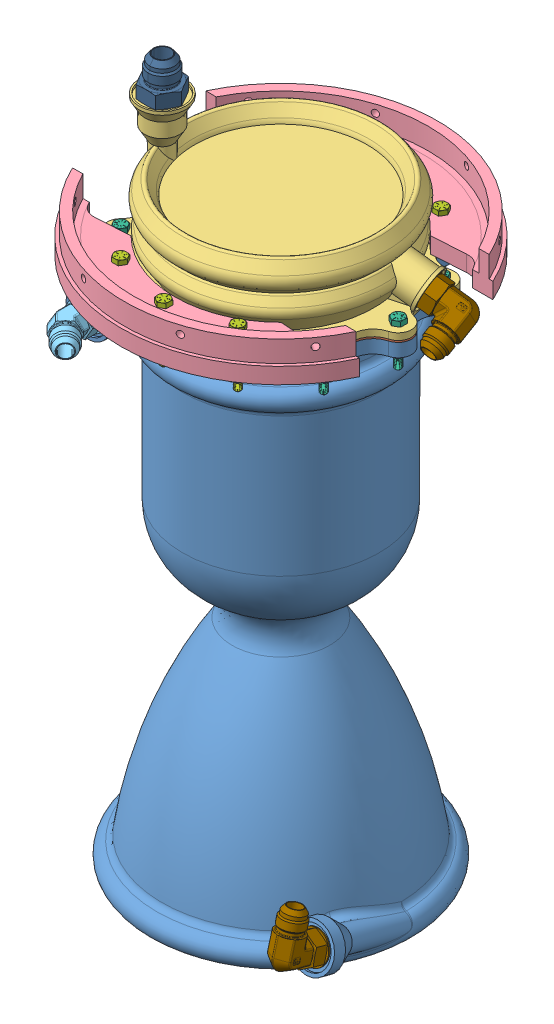
SolidWorks assembly 10013-R01_Engine, configuration Default. Lengths in mm.
Overall size (302.89 639.04 304.8).
32 component instances, 10 part files, 30 mates.
Components (placement in the parent):
- 13100_R02_Thrust_Chamber-2: 13100_R02_Thrust_Chamber [Default] at origin size (262.96 497.78 253.25)
- 13101-R01_TCA_GASKET-2: 13101-R01_TCA_GASKET [Default] at (0 280.7399 0) size (248.92 1.59 248.92)
- 13008-R01_Injector_Plate-2: 13008-R01_Injector_Plate [Default] at (150.3244 162.3751 158.3501) x (-0.965926 0 0.258819) z (-0.258819 0 -0.965926) size (243.88 107.11 241.3)
- 13007-R01_Thrust_Mount-3: 13007-R01_Thrust_Mount [Default] at (0 288.6774 0) x (0 0 -1) z (1 0 0) size (304.8 35.64 277.08)
- 15011-R01_10_FITTING_45-2: 15011-R01_10_FITTING_45 [Default] at (-93.6214 237.7504 111.76) size (44.94 39.22 63.51)
- 16011-R01_S_BOLT-13: 16011-R01_S_BOLT [90201A117] at (96.787 272.0087 55.88) x (0 -1 0) z (0 0 1) size (43.33 12.83 11.11)
- 16012-R01_L_BOLT-7: 16012-R01_L_BOLT [91257A550] at (55.88 280.7002 96.787) x (0 -1 0) z (0 0 1) size (55.63 12.83 11.11)
- 16013-R01_NUT-33: 16013-R01_NUT [94895A029] at (96.787 265.2618 55.88) x (-1 0 0) z (0 1 0) size (11.11 12.83 7.14)
- 15012-R01_10_FITTING_90-1: 15012-R01_10_FITTING_90 [Default] at (112.0104 282.4233 -26.0534) x (0.05538 -0.433018 0.899683) z (0.447836 0.816118 0.365232) size (51.49 55.55 29.29)
- 15012-R01_10_FITTING_90-2: 15012-R01_10_FITTING_90 [Default] at (102.5614 -170.5898 88.4045) x (0 0.965926 -0.258819) z (1 0 0) size (51.49 55.55 29.29)
- 15013-R01_12_FITTING_S-1: 15013-R01_12_FITTING_S [Default] at (-89.1216 396.9815 23.8801) x (0 1 0) z (0 0 1) size (50.04 36.67 31.75)
- 16011-R01_S_BOLT-14: 16011-R01_S_BOLT [90201A117] at (111.76 272.0087 0) x (0 -1 0) z (0.5 0 0.866025) size (43.33 12.83 11.11)
- 16011-R01_S_BOLT-15: 16011-R01_S_BOLT [90201A117] at (96.787 272.0087 -55.88) x (0 -1 0) z (0.866025 0 0.5) size (43.33 12.83 11.11)
- 16012-R01_L_BOLT-8: 16012-R01_L_BOLT [91257A550] at (0 280.7002 111.76) x (0 -1 0) z (-0.5 0 0.866025) size (55.63 12.83 11.11)
- 16012-R01_L_BOLT-9: 16012-R01_L_BOLT [91257A550] at (-55.88 280.7002 96.787) x (0 -1 0) z (-0.866025 0 0.5) size (55.63 12.83 11.11)
- 16012-R01_L_BOLT-10: 16012-R01_L_BOLT [91257A550] at (-55.88 280.7002 -96.787) x (0 -1 0) z (0 0 -1) size (55.63 12.83 11.11)
- 16012-R01_L_BOLT-11: 16012-R01_L_BOLT [91257A550] at (0 280.7002 -111.76) x (0 -1 0) z (0.5 0 -0.866025) size (55.63 12.83 11.11)
- 16012-R01_L_BOLT-12: 16012-R01_L_BOLT [91257A550] at (55.88 280.7002 -96.787) x (0 -1 0) z (0.866025 0 -0.5) size (55.63 12.83 11.11)
- 16011-R01_S_BOLT-16: 16011-R01_S_BOLT [90201A117] at (-96.787 272.0087 -55.88) x (0 -1 0) z (0 0 -1) size (43.33 12.83 11.11)
- 16011-R01_S_BOLT-17: 16011-R01_S_BOLT [90201A117] at (-111.76 272.0087 0) x (0 -1 0) z (-0.5 0 -0.866025) size (43.33 12.83 11.11)
- 16011-R01_S_BOLT-18: 16011-R01_S_BOLT [90201A117] at (-96.787 272.0087 55.88) x (0 -1 0) z (-0.866025 0 -0.5) size (43.33 12.83 11.11)
- 16013-R01_NUT-34: 16013-R01_NUT [94895A029] at (111.76 265.2618 0) x (-0.866025 0 0.5) z (0 1 0) size (11.11 12.83 7.14)
- 16013-R01_NUT-35: 16013-R01_NUT [94895A029] at (96.787 265.2618 -55.88) x (-0.5 0 0.866025) z (0 1 0) size (11.11 12.83 7.14)
- 16013-R01_NUT-36: 16013-R01_NUT [94895A029] at (55.88 265.2618 -96.787) x (0 0 1) z (0 1 0) size (11.11 12.83 7.14)
- 16013-R01_NUT-37: 16013-R01_NUT [94895A029] at (0 265.2618 -111.76) x (0.5 0 0.866025) z (0 1 0) size (11.11 12.83 7.14)
- 16013-R01_NUT-38: 16013-R01_NUT [94895A029] at (-55.88 265.2618 -96.787) x (0.866025 0 0.5) z (0 1 0) size (11.11 12.83 7.14)
- 16013-R01_NUT-39: 16013-R01_NUT [94895A029] at (-96.787 265.2618 -55.88) x (1 0 0) z (0 1 0) size (11.11 12.83 7.14)
- 16013-R01_NUT-40: 16013-R01_NUT [94895A029] at (-111.76 265.2618 0) x (0.866025 0 -0.5) z (0 1 0) size (11.11 12.83 7.14)
- 16013-R01_NUT-41: 16013-R01_NUT [94895A029] at (-96.787 265.2618 55.88) x (0.5 0 -0.866025) z (0 1 0) size (11.11 12.83 7.14)
- 16013-R01_NUT-42: 16013-R01_NUT [94895A029] at (-55.88 265.2618 96.787) x (0 0 -1) z (0 1 0) size (11.11 12.83 7.14)
- 16013-R01_NUT-43: 16013-R01_NUT [94895A029] at (0 265.2618 111.76) x (-0.5 0 -0.866025) z (0 1 0) size (11.11 12.83 7.14)
- 16013-R01_NUT-44: 16013-R01_NUT [94895A029] at (55.88 265.2618 96.787) x (-0.866025 0 -0.5) z (0 1 0) size (11.11 12.83 7.14)
Mates (geometry in assembly coordinates):
- Coincident1: coincident: plane of 13101-R01_TCA_GASKET-2 through (0 280.7399 0) normal (0 0 1); plane of assembly through (0 0 0) normal (0 0 1)
- Coincident2: coincident: plane of 13101-R01_TCA_GASKET-2 through (0 280.7399 0) normal (1 0 0); plane of assembly through (0 0 0) normal (1 0 0)
- Coincident3: coincident: plane of 13100_R02_Thrust_Chamber-2 through (87.2714 280.7399 0) normal (0 1 0); plane of 13101-R01_TCA_GASKET-2 through (0 280.7399 0) normal (0 -1 0)
- Coincident4: coincident: plane of 13101-R01_TCA_GASKET-2 through (0 282.3274 0) normal (0 1 0); plane of 13008-R01_Injector_Plate-2 through (0 282.3274 0) normal (0 -1 0)
- Concentric1: concentric: cylinder of 13100_R02_Thrust_Chamber-2 through (111.76 -217.044 0) axis (0 1 0) radius 3.302; cylinder of 13008-R01_Injector_Plate-2 through (111.76 298.0169 0) axis (0 -1 0) radius 3.302
- Concentric3: concentric: cylinder of 13100_R02_Thrust_Chamber-2 through (96.787 -217.044 -55.88) axis (0 1 0) radius 3.302; cylinder of 13008-R01_Injector_Plate-2 through (96.787 298.0169 -55.88) axis (0 -1 0) radius 3.302
- Parallel1: parallel: plane of 15012-R01_10_FITTING_90-2 through (102.5614 -170.5898 88.4045) normal (1 0 0); plane of assembly through (0 0 0) normal (1 0 0)
- Concentric5: concentric: cylinder of 13008-R01_Injector_Plate-2 through (-89.1216 282.3264 23.8801) axis (0 1 0) radius 9.525; cylinder of 15013-R01_12_FITTING_S-1 through (-89.1216 387.8045 23.8801) axis (0 -1 0) radius 13.3998
- Coincident7: coincident: plane of 13008-R01_Injector_Plate-2 through (-89.1216 387.0501 23.8801) normal (0 1 0); plane of 15013-R01_12_FITTING_S-1 through (-89.1216 387.0501 23.8801) normal (0 -1 0)
- Parallel2: parallel: plane of 15013-R01_12_FITTING_S-1 through (-89.1216 396.9815 23.8801) normal (0 0 1); plane of assembly through (0 0 0) normal (0 0 1)
- Concentric6: concentric: cylinder of 13100_R02_Thrust_Chamber-2 through (-93.6214 237.7504 0) axis (0 0 -1) radius 9.7828; cylinder of 15011-R01_10_FITTING_45-2 through (-93.6214 237.7504 85.581) axis (0 0 -1) radius 11.0268
- Coincident9: coincident: plane of 13100_R02_Thrust_Chamber-2 through (-93.6214 249.9892 87.884) normal (0 0 1); plane of 15011-R01_10_FITTING_45-2 through (-93.6214 237.7504 87.884) normal (0 0 -1)
- Parallel3: parallel: plane of 15011-R01_10_FITTING_45-2 through (-93.6214 237.7504 111.76) normal (0 1 0); plane of assembly through (0 0 0) normal (0 1 0)
- Coincident13: coincident: plane of 13008-R01_Injector_Plate-2 through (0 288.6774 0) normal (0 1 0); plane of 13007-R01_Thrust_Mount-3 through (0 288.6774 0) normal (0 -1 0)
- Concentric9: concentric: cylinder of 13008-R01_Injector_Plate-2 through (55.88 298.0169 96.787) axis (0 -1 0) radius 3.302; cylinder of 13007-R01_Thrust_Mount-3 through (55.88 288.6774 96.787) axis (0 1 0) radius 3.302
- Concentric10: concentric: cylinder of 13008-R01_Injector_Plate-2 through (55.88 298.0169 -96.787) axis (0 -1 0) radius 3.302; cylinder of 13007-R01_Thrust_Mount-3 through (55.88 288.6774 -96.787) axis (0 1 0) radius 3.302
- Coincident14: coincident: plane of 13007-R01_Thrust_Mount-3 through (0 303.9174 0) normal (0 1 0); plane of 16012-R01_L_BOLT-7 through (59.0879 303.9174 102.3432) normal (0 -1 0)
- Concentric11: concentric: cylinder of 13007-R01_Thrust_Mount-3 through (55.88 288.6774 96.787) axis (0 1 0) radius 3.302; cylinder of 16012-R01_L_BOLT-7 through (55.88 303.9174 96.787) axis (0 -1 0) radius 3.175
- Coincident15: coincident: plane of 13008-R01_Injector_Plate-2 through (0 288.6774 0) normal (0 1 0); plane of 16011-R01_S_BOLT-13 through (99.9949 288.6774 61.4363) normal (0 -1 0)
- Concentric12: concentric: cylinder of 13100_R02_Thrust_Chamber-2 through (96.787 -217.044 55.88) axis (0 1 0) radius 3.302; cylinder of 16011-R01_S_BOLT-13 through (96.787 288.6774 55.88) axis (0 -1 0) radius 3.175
- Coincident16: coincident: plane of 13100_R02_Thrust_Chamber-2 through (0 268.0399 0) normal (0 -1 0); plane of 16013-R01_NUT-33 through (102.3432 268.0399 59.0879) normal (0 1 0)
- Concentric13: concentric: circle of 16011-R01_S_BOLT-13; circle of 16013-R01_NUT-33
- Parallel6: parallel: plane of 16012-R01_L_BOLT-7 through (55.88 280.7002 96.787) normal (0 0 1); plane of assembly through (0 0 0) normal (0 0 1)
- Parallel7: parallel: plane of 16011-R01_S_BOLT-13 through (96.787 272.0087 55.88) normal (0 0 1); plane of assembly through (0 0 0) normal (0 0 1)
- Parallel8: parallel: plane of 16013-R01_NUT-33 through (96.787 265.2618 55.88) normal (-1 0 0); plane of assembly through (0 0 0) normal (1 0 0)
- Concentric14: concentric: cylinder of 13008-R01_Injector_Plate-2 through (-113.6468 396.6741 30.4516) axis (0.892399 -0.382683 -0.239118) radius 7.9375; cylinder of 15012-R01_10_FITTING_90-1 through (107.9057 301.6668 -28.9133) axis (0.892399 -0.382683 -0.239118) radius 11.0268
- Coincident17: coincident: plane of 13008-R01_Injector_Plate-2 through (110.0931 300.7288 -29.4994) normal (0.892399 -0.382683 -0.239118); plane of 15012-R01_10_FITTING_90-1 through (110.0931 300.7288 -29.4994) normal (-0.892399 0.382683 0.239118)
- Perpendicular2: perpendicular: plane of 13008-R01_Injector_Plate-2 through (0 288.6774 0) normal (0 1 0); plane of 15012-R01_10_FITTING_90-1 through (110.6498 307.017 -42.7965) normal (-0.258819 0 -0.965926)
- Concentric15: concentric: cylinder of 13100_R02_Thrust_Chamber-2 through (115.3836 -205.8035 0) axis (0 -0.258819 -0.965926) radius 9.7828; cylinder of 15012-R01_10_FITTING_90-2 through (115.3836 -184.0205 81.2951) axis (0 0.258819 0.965926) radius 11.0268
- Coincident19: coincident: plane of 13100_R02_Thrust_Chamber-2 through (115.3836 -171.5644 80.4951) normal (0 0.258819 0.965926); plane of 15012-R01_10_FITTING_90-2 through (115.3836 -183.3861 83.6627) normal (0 -0.258819 -0.965926)
